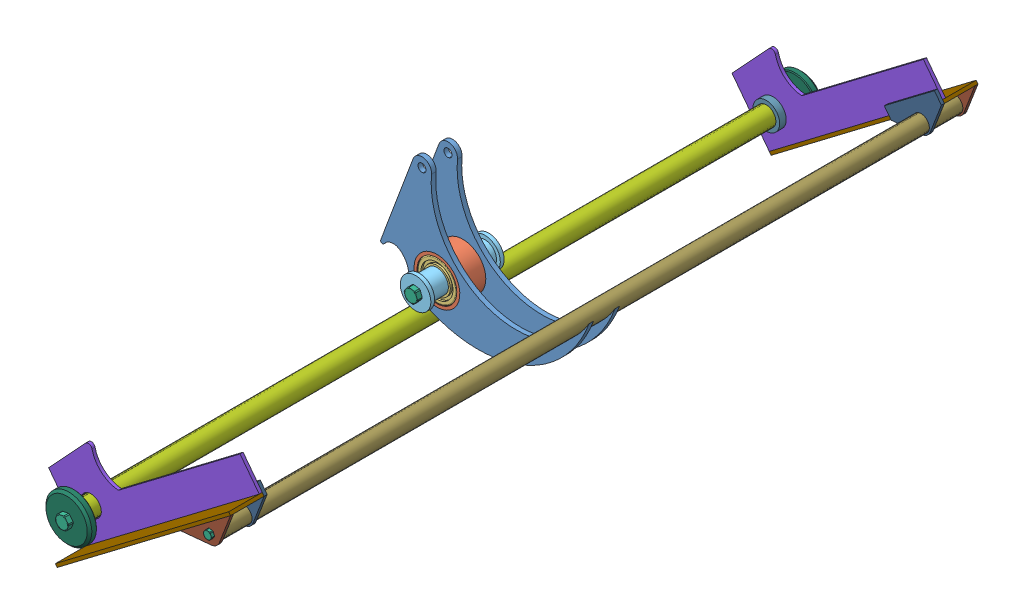
SolidWorks assembly ТП.016.03.00 - Подъем навесного оборудования, configuration 00. Lengths in mm.
Overall size (315.69 301.69 987.2).
34 component instances, 15 part files, 38 mates.
Components (placement in the parent):
- ТП.016.03.01.00 - Рычаг подъема навески-1: ТП.016.03.01.00 - Рычаг подъема навески [00] at (0 0 20) x (0.969039 0.246908 0) z (0 0 1) size (274.94 199.54 40) (flexible)
  - ТП.016.03.01.01 - Зуб подъемника (6мм)-1: ТП.016.03.01.01 - Зуб подъемника (6мм) [--] at origin size (274.94 199.54 6)
  - ТП.016.03.01.02 - Ступица подъема-1: ТП.016.03.01.02 - Ступица подъема [--] at (0 0 -20) x (0.998218 0.059675 0) z (0 0 1) size (60 60 40)
  - ТП.016.03.01.01 - Зуб подъемника (6мм)-2: ТП.016.03.01.01 - Зуб подъемника (6мм) [--] at (0 0 -34) size (274.94 199.54 6)
  - Подшипник ГОСТ 8338-75 -1: Подшипник ГОСТ 8338-75  [Подшипник 205 ГОСТ 8338-75] at (0 0 -7.5) x (0 0 -1) z (0.853055 -0.521822 0) size (15 52 52)
  - Подшипник ГОСТ 8338-75 -2: Подшипник ГОСТ 8338-75  [Подшипник 205 ГОСТ 8338-75] at (0 0 -32.5) x (0 0 -1) z (-0.395474 -0.918477 0) size (15 52 52)
- ТП.016.03.02 - Ось подъема-1: ТП.016.03.02 - Ось подъема [--] x (-0.846104 -0.533017 0) z (0 0 1) size (25 25 86)
- ТП.016.03.03 - Стакан оси подъема-1: ТП.016.03.03 - Стакан оси подъема [--] at (0 0 -20) x (-0.637116 -0.770768 0) z (0 0 -1) size (40 40 28)
- ТП.016.03.03 - Стакан оси подъема-2: ТП.016.03.03 - Стакан оси подъема [--] at (0 0 20) x (0.999679 0.025339 0) z (0 0 1) size (40 40 28)
- Болты с шестигранной головкой кт.В (ГОСТ 7798-70)-1: Болты с шестигранной головкой кт.В (ГОСТ 7798-70) [Болт М10-6gx20(S16) ГОСТ 7798-77] at (0 0 48) x (0 0 -1) z (-0.933904 -0.357524 0) size (26.4 17.6 16)
- Болты с шестигранной головкой кт.В (ГОСТ 7798-70)-2: Болты с шестигранной головкой кт.В (ГОСТ 7798-70) [Болт М10-6gx20(S16) ГОСТ 7798-77] at (0 0 -48) x (0 0 1) z (0.575817 -0.817579 0) size (26.4 17.6 16)
- ТП.016.03.04 - Ось крепления навески-1: ТП.016.03.04 - Ось крепления навески [--] at (-23.515 -52.1776 461.6) size (25 25 943.2)
- ТП.016.03.05.00 - Ложемент-1: ТП.016.03.05.00 - Ложемент [Правый] at (-23.515 -52.1776 449.6) x (0.79654 0.604586 0) z (0 0 1) size (285 120.68 48)
  - ТП.016.03.05.01 - Ложемент бок (4мм)-1: ТП.016.03.05.01 - Ложемент бок (4мм) [--] at origin size (285 93.38 4)
  - ТП.016.03.05.02 - Ложемент низ (4мм)-1: ТП.016.03.05.02 - Ложемент низ (4мм) [--] at (250 -35 -4) size (285 4 44)
  - ТП.016.03.05.03 - Хомут связки (4мм)-1: ТП.016.03.05.03 - Хомут связки (4мм) [--] at (250 -39 -4) size (82.5 38.3 4)
  - ТП.016.03.05.04 - Шайба связки (4мм)-1: ТП.016.03.05.04 - Шайба связки (4мм) [--] at (250 -39 40) size (82.5 23.3 4)
- ТП.016.03.05.00 - Ложемент-2: ТП.016.03.05.00 - Ложемент [Левый] at (-23.515 -52.1776 -445.6) x (0.79654 0.604586 0) z (0 0 1) size (285 120.68 48)
  - ТП.016.03.05.01 - Ложемент бок (4мм)-1: ТП.016.03.05.01 - Ложемент бок (4мм) [--] at origin size (285 93.38 4)
  - ТП.016.03.05.02 - Ложемент низ (4мм)-1: ТП.016.03.05.02 - Ложемент низ (4мм) [--] at (250 -35 -44) size (285 4 44)
  - ТП.016.03.05.03 - Хомут связки (4мм)-1: ТП.016.03.05.03 - Хомут связки (4мм) [--] at (250 -39 4) size (82.5 38.3 4)
  - ТП.016.03.05.04 - Шайба связки (4мм)-1: ТП.016.03.05.04 - Шайба связки (4мм) [--] at (250 -39 -40) size (82.5 23.3 4)
- ТП.016.03.06.00 - Штанга связки-1: ТП.016.03.06.00 - Штанга связки [00] at (-26.1598 98.6116 0) x (0.966166 -0.257922 0) z (0 0 1) size (21.43 21.43 971.2)
  - ТП.016.03.06.01 - Труба связка-1: ТП.016.03.06.01 - Труба связка [--] at (0 0 489.6) size (21.3 21.3 971.2)
  - ТП.016.03.06.02 - Втулка штанги-1: ТП.016.03.06.02 - Втулка штанги [--] at (198.0992 0 485.6) size (18 18 30)
  - ТП.016.03.06.02 - Втулка штанги-2: ТП.016.03.06.02 - Втулка штанги [--] at (216.8746 2.0316 -485.6) x (-0.976855 -0.213903 0) z (0 0 -1) size (18 18 30)
- Болты с шестигранной головкой кт.В (ГОСТ 7798-70)-3: Болты с шестигранной головкой кт.В (ГОСТ 7798-70) [Болт М6-6gx20(S10) ГОСТ 7798-77] at (172.7797 34.4811 489.6) x (0 0 -1) z (0.7882 -0.615419 0) size (24 10.9 10)
- Болты с шестигранной головкой кт.В (ГОСТ 7798-70)-4: Болты с шестигранной головкой кт.В (ГОСТ 7798-70) [Болт М6-6gx20(S10) ГОСТ 7798-77] at (172.7797 34.4811 -489.6) x (0 0 1) z (0.2792 0.960233 0) size (24 10.9 10)
- ТП.016.03.07 - Шайба проставка-1: ТП.016.03.07 - Шайба проставка [--] at (7.7544 4.8068 435) x (0.876683 -0.481068 0) z (0 0 1) size (35 35 8.6)
- ТП.016.03.07 - Шайба проставка-2: ТП.016.03.07 - Шайба проставка [--] at (28.2028 -12.8042 -443.6) x (0.605745 -0.795659 0) z (0 0 1) size (35 35 8.6)
- ТП.016.03.08 - Шайба законцовывающая-1: ТП.016.03.08 - Шайба законцовывающая [--] at (-23.515 -52.1776 471.6) x (0.993979 0.109574 0) z (0 0 1) size (60 60 10)
- ТП.016.03.08 - Шайба законцовывающая-2: ТП.016.03.08 - Шайба законцовывающая [--] at (-23.515 -52.1776 -471.6) x (0.95629 0.292419 0) z (0 0 -1) size (60 60 10)
- Болты с шестигранной головкой кт.В (ГОСТ 7798-70)-5: Болты с шестигранной головкой кт.В (ГОСТ 7798-70) [Болт М10-6gx20(S16) ГОСТ 7798-77] at (-23.515 -52.1776 -481.6) x (0 0 1) z (0.771641 -0.636059 0) size (26.4 17.6 16)
- Болты с шестигранной головкой кт.В (ГОСТ 7798-70)-6: Болты с шестигранной головкой кт.В (ГОСТ 7798-70) [Болт М10-6gx20(S16) ГОСТ 7798-77] at (-23.515 -52.1776 481.6) x (0 0 -1) z (0.165324 -0.986239 0) size (26.4 17.6 16)
Mates (geometry in assembly coordinates):
- Концентричный1: concentric: cylinder of ТП.016.03.01.00 - Рычаг подъема навески-1/Подшипник ГОСТ 8338-75 -1 through (0 0 1012.5) axis (0 0 1) radius 12.5; line of assembly
- Симметричный1: symmetric: plane of ТП.016.03.01.00 - Рычаг подъема навески-1/ТП.016.03.01.01 - Зуб подъемника (6мм)-1 through (53.6344 103.9824 14) normal (0 0 -1); plane of ТП.016.03.01.00 - Рычаг подъема навески-1/ТП.016.03.01.01 - Зуб подъемника (6мм)-2 through (53.6344 103.9824 -14) normal (0 0 1); plane of assembly
- Симметричный2: symmetric: plane of ТП.016.03.02 - Ось подъема-1 through (0 0 43) normal (0 0 1); plane of ТП.016.03.02 - Ось подъема-1 through (0 0 -43) normal (0 0 -1); plane of assembly
- Концентричный2: concentric: cylinder of ТП.016.03.01.00 - Рычаг подъема навески-1/Подшипник ГОСТ 8338-75 -2 through (0 0 987.5) axis (0 0 1) radius 12.5; cylinder of ТП.016.03.02 - Ось подъема-1 through (0 0 0) axis (0 0 1) radius 12.5
- Концентричный3: concentric: cylinder of ТП.016.03.02 - Ось подъема-1 through (0 0 0) axis (0 0 1) radius 12.5; cylinder of ТП.016.03.03 - Стакан оси подъема-1 through (0 0 -1020) axis (0 0 -1) radius 12.5
- Совпадение1: coincident: plane of ТП.016.03.03 - Стакан оси подъема-1 through (-15.4154 12.7423 -43) normal (0 0 1); plane of assembly through (0 0 -43) normal (0 0 -1)
- Совпадение2: coincident: plane of ТП.016.03.03 - Стакан оси подъема-2 through (-0.5068 19.9936 43) normal (0 0 -1); plane of assembly through (0 0 43) normal (0 0 1)
- Концентричный4: concentric: cylinder of ТП.016.03.02 - Ось подъема-1 through (0 0 0) axis (0 0 1) radius 12.5; cylinder of ТП.016.03.03 - Стакан оси подъема-2 through (0 0 1020) axis (0 0 1) radius 15
- Совпадение3: coincident: plane of ТП.016.03.03 - Стакан оси подъема-2 through (-0.133 5.2483 48) normal (0 0 1); plane of Болты с шестигранной головкой кт.В (ГОСТ 7798-70)-1 through (3.1462 -8.2184 48) normal (0 0 -1)
- Концентричный5: concentric: cylinder of ТП.016.03.02 - Ось подъема-1 through (0 0 43) axis (0 0 1) radius 4.25; cylinder of Болты с шестигранной головкой кт.В (ГОСТ 7798-70)-1 through (0 0 1048) axis (0 0 1) radius 5
- Совпадение4: coincident: plane of ТП.016.03.03 - Стакан оси подъема-1 through (-4.0465 3.3449 -48) normal (0 0 -1); plane of Болты с шестигранной головкой кт.В (ГОСТ 7798-70)-2 through (-7.1947 -5.0672 -48) normal (0 0 1)
- Концентричный6: concentric: cylinder of ТП.016.03.02 - Ось подъема-1 through (0 0 -43) axis (0 0 -1) radius 4.25; cylinder of Болты с шестигранной головкой кт.В (ГОСТ 7798-70)-2 through (0 0 -1048) axis (0 0 -1) radius 5
- Концентричный7: concentric: cylinder of ТП.016.03.04 - Ось крепления навески-1 through (-23.515 -52.1776 -35.3553) axis (0 0 1) radius 12.5; circle of assembly
- Симметричный3: symmetric: plane of ТП.016.03.04 - Ось крепления навески-1 through (-23.515 -52.1776 -471.6) normal (0 0 -1); plane of ТП.016.03.04 - Ось крепления навески-1 through (-23.515 -52.1776 471.6) normal (0 0 1); plane of assembly
- Концентричный8: concentric: cylinder of ТП.016.03.04 - Ось крепления навески-1 through (-23.515 -52.1776 -35.3553) axis (0 0 1) radius 12.5; cylinder of ТП.016.03.05.00 - Ложемент-1/ТП.016.03.05.01 - Ложемент бок (4мм)-1 through (-23.515 -52.1776 445.6) axis (0 0 1) radius 13.5
- Концентричный9: concentric: cylinder of ТП.016.03.04 - Ось крепления навески-1 through (-23.515 -52.1776 -35.3553) axis (0 0 1) radius 12.5; cylinder of ТП.016.03.05.00 - Ложемент-2/ТП.016.03.05.01 - Ложемент бок (4мм)-1 through (-23.515 -52.1776 -449.6) axis (0 0 1) radius 13.5
- Концентричный10: concentric: cylinder of ТП.016.03.05.00 - Ложемент-1/ТП.016.03.05.03 - Хомут связки (4мм)-1 through (172.7797 34.4811 441.6) axis (0 0 1) radius 10.65; cylinder of ТП.016.03.06.00 - Штанга связки-1/ТП.016.03.06.01 - Труба связка-1 through (172.7797 34.4811 -30.1227) axis (0 0 1) radius 10.65
- Совпадение9: coincident: plane of ТП.016.03.05.00 - Ложемент-1/ТП.016.03.05.04 - Шайба связки (4мм)-1 through (172.7797 34.4811 485.6) normal (0 0 -1); plane of ТП.016.03.06.00 - Штанга связки-1/ТП.016.03.06.01 - Труба связка-1 through (172.7797 34.4811 485.6) normal (0 0 1)
- Концентричный11: concentric: cylinder of ТП.016.03.05.00 - Ложемент-2/ТП.016.03.05.03 - Хомут связки (4мм)-1 through (172.7797 34.4811 -445.6) axis (0 0 1) radius 10.65; cylinder of ТП.016.03.06.00 - Штанга связки-1/ТП.016.03.06.01 - Труба связка-1 through (172.7797 34.4811 -30.1227) axis (0 0 1) radius 10.65
- Касательность1: tangent: cylinder of ТП.016.03.01.00 - Рычаг подъема навески-1/ТП.016.03.01.01 - Зуб подъемника (6мм)-1 through (103.5561 107.2717 14) axis (0 0 1) radius 111.1009; cylinder of ТП.016.03.06.00 - Штанга связки-1/ТП.016.03.06.01 - Труба связка-1 through (172.7797 34.4811 -30.1227) axis (0 0 1) radius 10.65
- Совпадение10: coincident: plane of ТП.016.03.05.00 - Ложемент-1/ТП.016.03.05.04 - Шайба связки (4мм)-1 through (172.7797 34.4811 489.6) normal (0 0 1); plane of Болты с шестигранной головкой кт.В (ГОСТ 7798-70)-3 through (176.1337 38.7768 489.6) normal (0 0 -1)
- Концентричный12: concentric: cylinder of ТП.016.03.06.00 - Штанга связки-1/ТП.016.03.06.02 - Втулка штанги-1 through (172.7797 34.4811 485.6) axis (0 0 1) radius 2.5; cylinder of Болты с шестигранной головкой кт.В (ГОСТ 7798-70)-3 through (172.7797 34.4811 1489.6) axis (0 0 1) radius 3
- Концентричный13: concentric: cylinder of ТП.016.03.06.00 - Штанга связки-1/ТП.016.03.06.02 - Втулка штанги-2 through (172.7797 34.4811 -485.6) axis (0 0 -1) radius 2.5; cylinder of Болты с шестигранной головкой кт.В (ГОСТ 7798-70)-4 through (172.7797 34.4811 -1489.6) axis (0 0 -1) radius 3
- Совпадение11: coincident: plane of ТП.016.03.05.00 - Ложемент-2/ТП.016.03.05.04 - Шайба связки (4мм)-1 through (172.7797 34.4811 -489.6) normal (0 0 -1); plane of Болты с шестигранной головкой кт.В (ГОСТ 7798-70)-4 through (178.0129 32.9594 -489.6) normal (0 0 1)
- Концентричный14: concentric: cylinder of ТП.016.03.04 - Ось крепления навески-1 through (-23.515 -52.1776 -35.3553) axis (0 0 1) radius 12.5; cylinder of ТП.016.03.07 - Шайба проставка-1 through (-23.515 -52.1776 495.0975) axis (0 0 -1) radius 12.5
- Расстояние1: distance = 28 mm: plane of ТП.016.03.04 - Ось крепления навески-1 through (-23.515 -52.1776 471.6) normal (0 0 1); plane of ТП.016.03.07 - Шайба проставка-1 through (49.2422 -92.6444 443.6) normal (0 0 1)
- Расстояние2: distance = 2 mm: plane of ТП.016.03.05.00 - Ложемент-1/ТП.016.03.05.01 - Ложемент бок (4мм)-1 through (15.1916 21.5311 445.6) normal (0 0 -1); plane of ТП.016.03.07 - Шайба проставка-1 through (49.2422 -92.6444 443.6) normal (0 0 1)
- Концентричный15: concentric: cylinder of ТП.016.03.04 - Ось крепления навески-1 through (-23.515 -52.1776 -35.3553) axis (0 0 1) radius 12.5; cylinder of ТП.016.03.07 - Шайба проставка-2 through (-23.515 -52.1776 -383.5025) axis (0 0 -1) radius 12.5
- Расстояние3: distance = 28 mm: plane of ТП.016.03.07 - Шайба проставка-2 through (-23.515 -52.1776 -443.6) normal (0 0 -1); plane of ТП.016.03.04 - Ось крепления навески-1 through (-23.515 -52.1776 -471.6) normal (0 0 -1)
- Расстояние4: distance = 2 mm: plane of ТП.016.03.05.00 - Ложемент-2/ТП.016.03.05.01 - Ложемент бок (4мм)-1 through (15.1916 21.5311 -445.6) normal (0 0 1); plane of ТП.016.03.07 - Шайба проставка-2 through (-23.515 -52.1776 -443.6) normal (0 0 -1)
- Совпадение12: coincident: plane of ТП.016.03.04 - Ось крепления навески-1 through (-23.515 -52.1776 471.6) normal (0 0 1); plane of ТП.016.03.08 - Шайба законцовывающая-1 through (-23.515 -52.1776 471.6) normal (0 0 -1)
- Концентричный16: concentric: cylinder of ТП.016.03.04 - Ось крепления навески-1 through (-23.515 -52.1776 471.6) axis (0 0 1) radius 4.25; cylinder of ТП.016.03.08 - Шайба законцовывающая-1 through (-23.515 -52.1776 481.6) axis (0 0 -1) radius 5.25
- Совпадение13: coincident: plane of ТП.016.03.04 - Ось крепления навески-1 through (-23.515 -52.1776 -471.6) normal (0 0 -1); plane of ТП.016.03.08 - Шайба законцовывающая-2 through (-23.515 -52.1776 -471.6) normal (0 0 1)
- Концентричный17: concentric: cylinder of ТП.016.03.04 - Ось крепления навески-1 through (-23.515 -52.1776 -471.6) axis (0 0 -1) radius 4.25; cylinder of ТП.016.03.08 - Шайба законцовывающая-2 through (-23.515 -52.1776 -481.6) axis (0 0 1) radius 5.25
- Совпадение14: coincident: plane of ТП.016.03.08 - Шайба законцовывающая-2 through (-23.515 -52.1776 -481.6) normal (0 0 -1); plane of Болты с шестигранной головкой кт.В (ГОСТ 7798-70)-5 through (-29.1123 -58.9681 -481.6) normal (0 0 1)
- Концентричный18: concentric: cylinder of ТП.016.03.08 - Шайба законцовывающая-2 through (-23.515 -52.1776 -481.6) axis (0 0 1) radius 5.25; cylinder of Болты с шестигранной головкой кт.В (ГОСТ 7798-70)-5 through (-23.515 -52.1776 -1481.6) axis (0 0 -1) radius 5
- Совпадение15: coincident: plane of ТП.016.03.08 - Шайба законцовывающая-1 through (-23.515 -52.1776 481.6) normal (0 0 1); plane of Болты с шестигранной головкой кт.В (ГОСТ 7798-70)-6 through (-14.8361 -50.7228 481.6) normal (0 0 -1)
- Концентричный19: concentric: cylinder of ТП.016.03.08 - Шайба законцовывающая-1 through (-23.515 -52.1776 481.6) axis (0 0 -1) radius 5.25; cylinder of Болты с шестигранной головкой кт.В (ГОСТ 7798-70)-6 through (-23.515 -52.1776 1481.6) axis (0 0 1) radius 5
